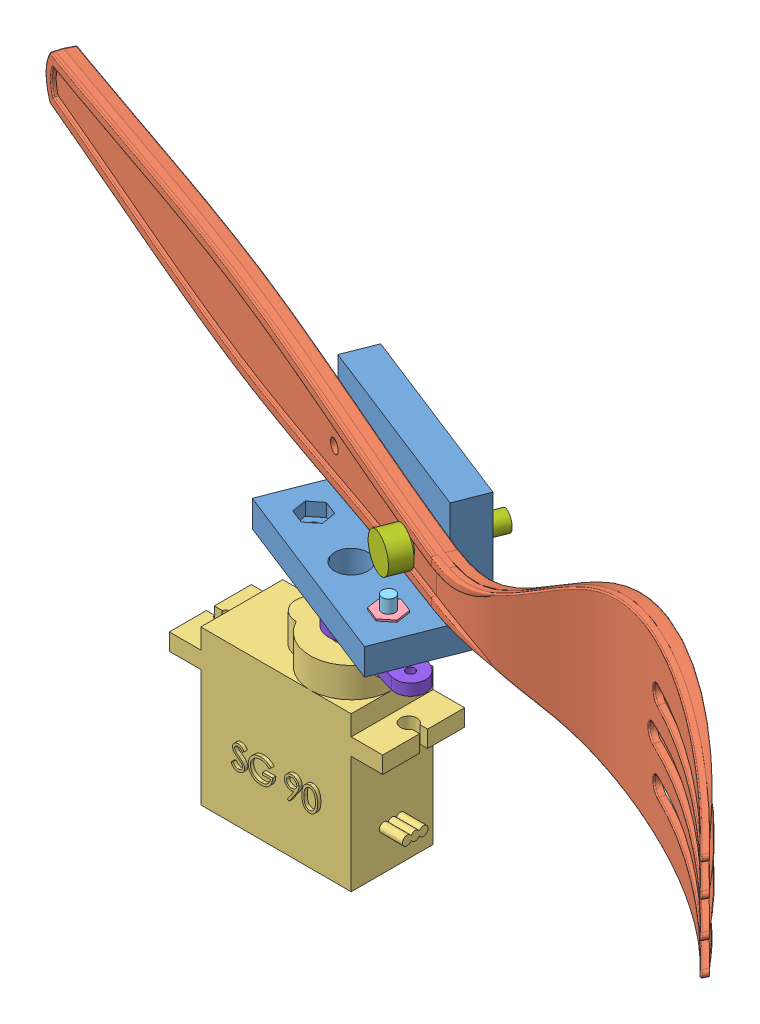
SolidWorks assembly Fork Assem, configuration Default. Lengths in mm.
Overall size (169.69 61.86 84.19).
8 component instances, 8 part files, 17 mates.
Components (placement in the parent):
- End Bracket-1: End Bracket [Default] at (25.9583 -13.3207 38.4728) x (0.930985 0 0.365056) z (-0.365056 0 0.930985) size (30 20 15)
- Fork-1: Fork [Default] at (27.017 -1.3207 35.773) x (-0.930985 0 -0.365056) z (0 1 0) size (173.48 22.4 33.6)
- servo SG90-1: servo SG90 [Predeterminado] at (20.7833 -28.6279 38.4728) size (32.27 31.33 12.9)
- m2 nut-1: m2 nut [Default] at (35.2682 -11.3207 42.1234) x (-0.623729 0 -0.781641) z (0.781641 0 -0.623729) size (3.92 2.28 4.53)
- m2x8-1: m2x8 [Default] at (35.2682 -15.0479 42.1234) x (-0.945382 0 -0.325965) z (-0.325965 0 0.945382) size (3.68 9.88 3.68)
- m3 nut-1: m3 nut [Default] at (38.8384 -1.3207 33.0184) x (-0.465493 0.866025 -0.182528) z (0.806257 0.5 0.316148) size (5.5 2.28 6.35)
- m3x12-1: m3x12 [Default] at (35.9253 -1.3207 40.4476) x (0.581559 -0.780889 0.22804) z (-0.726996 -0.62467 -0.285068) size (5.44 15 5.44)
- Micro Servo Horn Arm-1: Micro Servo Horn Arm [Default] at (25.9583 -17.5879 38.4728) x (0.930985 0 0.365056) z (-0.365056 0 0.930985) size (36.39 4.27 7.53)
Mates (geometry in assembly coordinates):
- Concentric1: concentric aligned: cylinder of servo SG90-1 through (25.9583 -15.0479 38.4728) axis (0 -1 0) radius 2.45; cylinder of Micro Servo Horn Arm-1 through (25.9583 -15.0479 38.4728) axis (0 -1 0) radius 2.2352
- Coincident1: coincident anti-aligned: plane of servo SG90-1 through (25.9583 -15.0479 38.4728) normal (0 1 0); plane of Micro Servo Horn Arm-1 through (-1.0968 -15.0479 27.864) normal (0 -1 0)
- Coincident2: coincident anti-aligned: plane of End Bracket-1 through (41.7484 6.6793 39.2937) normal (-0.365056 0 0.930985); plane of Fork-1 through (-46.6952 -1.4829 4.6134) normal (0.365056 0 -0.930985)
- Concentric4: concentric aligned: cylinder of Fork-1 through (42.6032 -1.3207 23.4173) axis (-0.365056 0 0.930985) radius 1; cylinder of m3x12-1 through (40.3059 -1.3207 29.2758) axis (-0.365056 0 0.930985) radius 1.44
- Coincident4: coincident aligned: plane of Fork-1 through (-4.6702 4.5695 24.5294) normal (-0.365056 0 0.930985); circle of m3x12-1
- Concentric5: concentric anti-aligned: cylinder of m2x8-1 through (35.2682 -7.0479 42.1234) axis (0 -1 0) radius 0.98; cylinder of Micro Servo Horn Arm-1 through (35.2682 -17.5879 42.1234) axis (0 1 0) radius 0.98
- Coincident5: coincident aligned: circle of m2x8-1; plane of Micro Servo Horn Arm-1 through (-1.0968 -15.0479 27.864) normal (0 -1 0)
- Coincident6: coincident: plane of End Bracket-1 through (25.9583 -13.3207 38.4728) normal (0 -1 0); line of Micro Servo Horn Arm-1 through (25.7121 -13.3207 42.3619) axis (0.961106 0 0.276179)
- Concentric6: concentric aligned: cylinder of End Bracket-1 through (35.2682 -9.3207 42.1234) axis (0 -1 0) radius 1; cylinder of m2x8-1 through (35.2682 -7.0479 42.1234) axis (0 -1 0) radius 0.98
- Concentric7: concentric anti-aligned: cylinder of End Bracket-1 through (16.6485 -9.3207 34.8223) axis (0 -1 0) radius 1; cylinder of Micro Servo Horn Arm-1 through (16.6485 -17.5879 34.8223) axis (0 1 0) radius 0.98
- Concentric8: concentric anti-aligned: cylinder of m2 nut-1 through (35.2682 -9.0407 42.1234) axis (0 -1 0) radius 0.98; cylinder of m2x8-1 through (35.2682 -16.9279 42.1234) axis (0 1 0) radius 1.84
- Coincident7: coincident: plane of End Bracket-1 through (25.9583 -11.3207 38.4728) normal (0 1 0); line of m2 nut-1 through (37.0372 -11.3207 40.7118) axis (-0.930985 0 -0.365056)
- Coincident8: coincident anti-aligned: plane of End Bracket-1 through (37.0372 -11.3207 40.7118) normal (-0.365056 0 0.930985); plane of m2 nut-1 through (37.0372 -9.0407 40.7118) normal (0.365056 0 -0.930985)
- Concentric9: concentric anti-aligned: cylinder of m3 nut-1 through (38.0061 -1.3207 35.141) axis (0.365056 0 -0.930985) radius 1.25; cylinder of m3x12-1 through (40.3059 -1.3207 29.2758) axis (-0.365056 0 0.930985) radius 1.44
- Coincident9: coincident: plane of End Bracket-1 through (28.6962 -13.3207 31.4904) normal (0.365056 0 -0.930985); line of m3 nut-1 through (35.4459 0.2671 34.1371) axis (0 -1 0)
- Concentric11: concentric aligned: cylinder of End Bracket-1 through (20.299 -1.3207 25.5124) axis (-0.365056 0 0.930985) radius 1.44; cylinder of Fork-1 through (23.9835 -1.3207 16.1162) axis (-0.365056 0 0.930985) radius 1
- Concentric13: concentric aligned: cylinder of End Bracket-1 through (38.9187 -1.3207 32.8135) axis (-0.365056 0 0.930985) radius 1.44; cylinder of m3x12-1 through (40.3059 -1.3207 29.2758) axis (-0.365056 0 0.930985) radius 1.44
